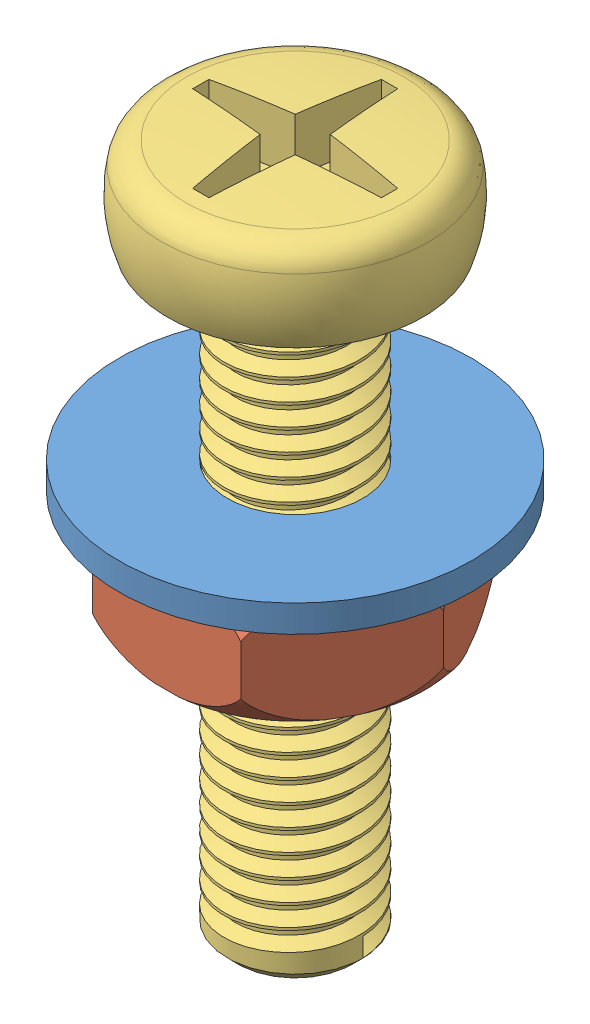
SolidWorks assembly Screw 5mm total Asm - Short, configuration Default. Lengths in mm.
Overall size (13.87 25.49 13.87).
3 component instances, 3 part files, 3 mates.
Components (placement in the parent):
- Ross 5 mm-1: Ross 5 mm [Default] at (4.2075 -20.4507 21.8965) x (0.997618 0 0.068982) z (-0.068982 0 0.997618) size (13 1 13)
- Nut 5 mm-1: Nut 5 mm [Default] at (4.2075 -23.4507 21.8965) size (11.46 4.49 10.93)
- Screw 5mm - short-1: Screw 5mm - short [Default] at (4.2075 -13.2778 21.8965) size (10 25.49 10)
Mates (geometry in assembly coordinates):
- Coincident1: coincident aligned: circle of Ross 5 mm-1; circle of Nut 5 mm-1
- Coincident2: coincident anti-aligned: plane of Ross 5 mm-1 through (4.2075 -20.4507 21.8965) normal (0 1 0)
- Concentric1: concentric anti-aligned: circle of Ross 5 mm-1; circle of Screw 5mm - short-1
